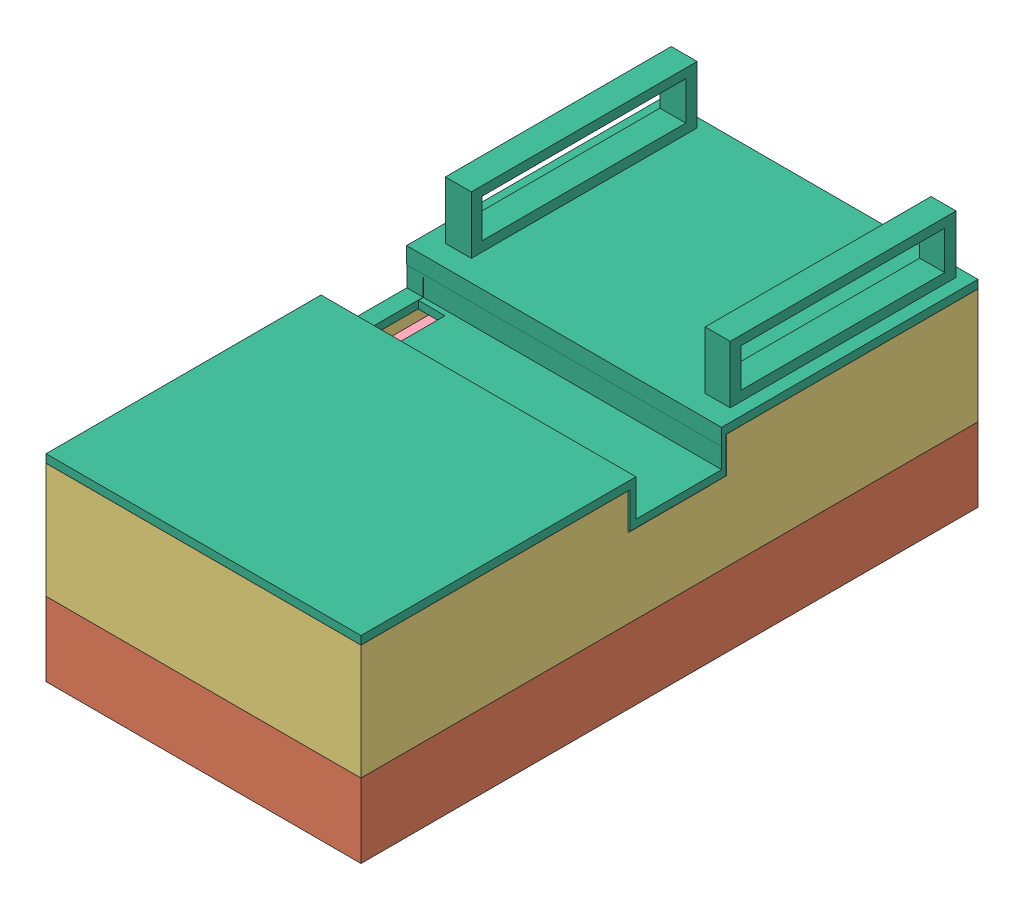
SolidWorks assembly Assembly, configuration Predeterminado. Lengths in mm.
Overall size (39.21 31 75).
73 component instances, 24 part files, 9 mates.
Components (placement in the parent):
- Batery-1: Batery [Predeterminado] at (30.2546 13.9223 39.5238) size (18 7 52)
- BatterySlot-1: BatterySlot [Predeterminado] at (30.3046 11.7897 39.4738) size (38.3 12 75)
- PCBSlot-1: PCBSlot [Predeterminado] at (30.3046 20.7768 39.4738) size (38.3 14 75)
- TFG_PSoC_PCB.step-1: TFG_PSoC_PCB.step [Predeterminado] at (15.3186 27.933 71.5458) x (1 0 0) z (0 1 0) size (30.68 63.5 8.39)
  - Board.step-1: Board.step [Predeterminado] at origin size (28.96 63.5 1.13)
    - Open CASCADE STEP translator 6.8 1.1.1.step-1: Open CASCADE STEP translator 6.8 1.1.1.step [Predeterminado] at (0 0 -1.1244) size (28.96 63.5 1.13)
  - R6.step-1: R6.step [Predeterminado] at origin size (1.6 0.8 0.45)
    - 0603_resistor.step-1: 0603_resistor.step [Predeterminado] at (19.3041 13.697 0) x (-1 0 0) z (0 1 0) size (1.6 0.45 0.8)
  - D3.step-1: D3.step [Predeterminado] at origin size (3.2 1.6 0.9)
    - LED_1206_Base_BLUE.step-1: LED_1206_Base_BLUE.step [Predeterminado] at (3.1748 36.322 0) x (-1 0 0) z (0 1 0) size (3.2 0.4 1.6)
    - LED_1206_Lens_BLUE.step-1: LED_1206_Lens_BLUE.step [Predeterminado] at (3.1749 36.3219 0) x (-1 0 0) z (0 1 0) size (1.5 0.6 1.6)
  - U4.step-1: U4.step [Predeterminado] at origin size (2.9 2.7 1.45)
    - OT.step-1: OT.step [Predeterminado] at (15.3671 10.9219 0) x (1 0 0) z (0 -1 0) size (2.9 1.45 2.7)
  - U3.step-1: U3.step [Predeterminado] at origin size (6.5 7 1.8)
    - ADP3338AKCZ-3.3-RL.step-1: ADP3338AKCZ-3.3-RL.step [Predeterminado] at (25.2731 8.0009 0) x (0 -1 0) z (-1 0 0) size (7 1.8 6.5)
  - U2.step-1: U2.step [Predeterminado] at origin size (13.5 18.5 1.8)
    - HM11.step-1: HM11.step [Predeterminado] at (18.034 20.9359 -1.1244) x (1 0 0) z (0 0 -1) size (13.5 18.5 1.8)
  - U1.step-1: U1.step [Predeterminado] at origin size (8.1 8.1 1)
    - 6140338960.step-1: 6140338960.step [Predeterminado] at (14.224 43.942 0) x (1 0 0) z (0 0 1) size (8.1 8.1 1)
  - S1.step-1: S1.step [Predeterminado] at origin size (7.39 10.49 3.05)
    - NKK_SS312SAH4.step-1: NKK_SS312SAH4.step [Predeterminado] at (2.2801 20.701 0) x (0 -1 0) z (-1 0 0) size (10.49 3.05 7.39)
      - SS312SAH4.step-1: SS312SAH4.step [Predeterminado] at (0 1.4478 0) size (10.49 3.05 7.39)
        - SS312SAH4body.step-1: SS312SAH4body.step [Predeterminado] at origin size (9.45 2.9 3.99)
        - SS312SAH4actu.step-1: SS312SAH4actu.step [Predeterminado] at (0 0.5588 1.9431) x (1 0 0) z (0 -1 0) size (3.51 2.31 1.19)
        - SS312SAH4trmnls.step-1: SS312SAH4trmnls.step [Predeterminado] at (0 0 -1.8669) size (4.62 1.72 1.8)
        - SS312SAH4brac.step-1: SS312SAH4brac.step [Predeterminado] at origin size (10.49 2.9 3.99)
  - R5.step-1: R5.step [Predeterminado] at origin size (0.8 1.6 0.45)
    - 0603_resistor.step-1: 0603_resistor.step [Predeterminado] at (18.65 35.8139 0) x (0 1 0) z (1 0 0) size (1.6 0.45 0.8)
  - R4.step-1: R4.step [Predeterminado] at origin size (1.6 0.8 0.45)
    - 0603_resistor.step-1: 0603_resistor.step [Predeterminado] at (23.4951 51.797 0) x (-1 0 0) z (0 1 0) size (1.6 0.45 0.8)
  - R3.step-1: R3.step [Predeterminado] at origin size (1.6 0.8 0.45)
    - 0603_resistor.step-1: 0603_resistor.step [Predeterminado] at (15.4941 6.839 0) x (-1 0 0) z (0 1 0) size (1.6 0.45 0.8)
  - R2.step-1: R2.step [Predeterminado] at origin size (0.8 1.6 0.45)
    - 0603_resistor.step-1: 0603_resistor.step [Predeterminado] at (12.211 7.2391 0) x (0 -1 0) z (-1 0 0) size (1.6 0.45 0.8)
  - R1.step-1: R1.step [Predeterminado] at origin size (0.8 1.6 0.45)
    - 0603_resistor.step-1: 0603_resistor.step [Predeterminado] at (12.211 10.2871 0) x (0 -1 0) z (-1 0 0) size (1.6 0.45 0.8)
  - J2.step-1: J2.step [Predeterminado] at origin size (7.9 8.94 3.96)
    - Molex_-_1054500101_v7.step-1: Molex_-_1054500101_v7.step [Predeterminado] at (4.6431 8.7717 0) x (0 1 0) z (0 0 1) size (8.94 7.9 3.96)
  - J1.step-1: J1.step [Predeterminado] at origin size (6.35 5.84 5.97)
    - 6140336880.step-1: 6140336880.step [Predeterminado] at (3.556 54.8868 0) x (-1 0 0) z (0 1 0) size (6.35 5.97 5.84)
  - D2.step-1: D2.step [Predeterminado] at origin size (3.2 1.6 0.9)
    - LED_1206_Base_GREEN.step-1: LED_1206_Base_GREEN.step [Predeterminado] at (3.1748 31.877 0) x (-1 0 0) z (0 1 0) size (3.2 0.4 1.6)
    - LED_1206_Lens_GREEN.step-1: LED_1206_Lens_GREEN.step [Predeterminado] at (3.1749 31.8769 0) x (-1 0 0) z (0 1 0) size (1.5 0.6 1.6)
  - D1.step-1: D1.step [Predeterminado] at origin size (3.2 1.6 0.9)
    - LED_1206_Lens_YELLOW.step-1: LED_1206_Lens_YELLOW.step [Predeterminado] at (3.1751 29.2728 0) x (1 0 0) z (0 -1 0) size (1.5 0.6 1.6)
    - LED_1206_Base_YELLOW.step-1: LED_1206_Base_YELLOW.step [Predeterminado] at (3.1752 29.2728 0) x (1 0 0) z (0 -1 0) size (3.2 0.4 1.6)
  - C13.step-1: C13.step [Predeterminado] at origin size (0.82 1.6 0.82)
    - 0603_cap.step-1: 0603_cap.step [Predeterminado] at (13.4621 57.2769 0) x (0 -1 0) z (-1 0 0) size (1.6 0.82 0.82)
  - C12.step-1: C12.step [Predeterminado] at origin size (0.82 1.6 0.82)
    - 0603_cap.step-1: 0603_cap.step [Predeterminado] at (15.2664 57.2769 0) x (0 -1 0) z (-1 0 0) size (1.6 0.82 0.82)
  - C11.step-1: C11.step [Predeterminado] at origin size (0.82 1.6 0.82)
    - 0603_cap.step-1: 0603_cap.step [Predeterminado] at (10.0329 35.6871 0) x (0 1 0) z (1 0 0) size (1.6 0.82 0.82)
  - C10.step-1: C10.step [Predeterminado] at origin size (0.82 1.6 0.82)
    - 0603_cap.step-1: 0603_cap.step [Predeterminado] at (8.2287 35.6871 0) x (0 1 0) z (1 0 0) size (1.6 0.82 0.82)
  - C9.step-1: C9.step [Predeterminado] at origin size (1.6 0.82 0.82)
    - 0603_cap.step-1: 0603_cap.step [Predeterminado] at (23.4949 49.7839 0) x (-1 0 0) z (0 1 0) size (1.6 0.82 0.82)
  - C8.step-1: C8.step [Predeterminado] at origin size (1.6 0.82 0.82)
    - 0603_cap.step-1: 0603_cap.step [Predeterminado] at (23.4949 47.8789 0) x (-1 0 0) z (0 1 0) size (1.6 0.82 0.82)
  - C7.step-1: C7.step [Predeterminado] at origin size (0.82 1.6 0.82)
    - 0603_cap.step-1: 0603_cap.step [Predeterminado] at (10.2871 57.2369 0) x (0 -1 0) z (-1 0 0) size (1.6 0.82 0.82)
  - C6.step-1: C6.step [Predeterminado] at origin size (0.82 1.6 0.82)
    - 0603_cap.step-1: 0603_cap.step [Predeterminado] at (4.5721 39.2429 0) x (0 -1 0) z (-1 0 0) size (1.6 0.82 0.82)
  - C5.step-1: C5.step [Predeterminado] at origin size (0.82 1.6 0.82)
    - 0603_cap.step-1: 0603_cap.step [Predeterminado] at (18.2881 54.9509 0) x (0 -1 0) z (-1 0 0) size (1.6 0.82 0.82)
  - C4.step-1: C4.step [Predeterminado] at origin size (1.6 0.82 0.82)
    - 0603_cap.step-1: 0603_cap.step [Predeterminado] at (26.5429 13.3349 0) x (-1 0 0) z (0 1 0) size (1.6 0.82 0.82)
  - C3.step-1: C3.step [Predeterminado] at origin size (0.82 1.6 0.82)
    - 0603_cap.step-1: 0603_cap.step [Predeterminado] at (18.6691 10.4539 0) x (0 -1 0) z (-1 0 0) size (1.6 0.82 0.82)
  - C2.step-1: C2.step [Predeterminado] at origin size (1.27 2 1.27)
    - 0805_cap.step-1: 0805_cap.step [Predeterminado] at (18.032 6.4771 0.62) x (0 -1 0) z (0 0 1) size (2 1.27 1.27)
  - C1.step-1: C1.step [Predeterminado] at origin size (1.27 2 1.27)
    - 0805_cap.step-1: 0805_cap.step [Predeterminado] at (10.416 8.6739 0.62) x (0 1 0) z (0 0 1) size (2 1.27 1.27)
- TAPA-3: TAPA [Predeterminado] at (30.2994 35.7867 39.4738) x (-1 0 0) z (0 0 1) size (38.29 12.38 75)
Mates (geometry in assembly coordinates):
- Coincidente1: coincident anti-aligned: plane of Batery-1 through (21.2546 20.9223 65.5238) normal (0 0 1); plane of BatterySlot-1 through (30.3046 13.5897 65.5238) normal (0 0 -1)
- Coincidente2: coincident anti-aligned: plane of Batery-1 through (21.2546 20.9223 13.5238) normal (-1 0 0); plane of BatterySlot-1 through (21.2546 13.5897 39.4738) normal (1 0 0)
- Paralelo7: parallel anti-aligned: plane of PCBSlot-1 through (30.3046 20.7768 39.4738) normal (0 -1 0); plane of TFG_PSoC_PCB.step-1/Board.step-1/Open CASCADE STEP translator 6.8 1.1.1.step-1 through (15.3186 27.933 71.5458) normal (0 1 0)
- Concéntrica23: concentric aligned: cylinder of PCBSlot-1 through (42.3696 31.7768 69.5138) axis (0 -1 0) radius 1.14; cylinder of TFG_PSoC_PCB.step-1/Board.step-1/Open CASCADE STEP translator 6.8 1.1.1.step-1 through (42.3696 26.8086 69.5138) axis (0 -1 0) radius 1.27
- Concéntrica27: concentric aligned: cylinder of PCBSlot-1 through (42.3696 31.7768 9.8238) axis (0 -1 0) radius 1.14; cylinder of TFG_PSoC_PCB.step-1/Board.step-1/Open CASCADE STEP translator 6.8 1.1.1.step-1 through (42.3696 26.8086 9.8238) axis (0 -1 0) radius 1.27
- Concéntrica28: concentric aligned: cylinder of PCBSlot-1 through (33.6567 31.7768 74.3238) axis (0 1 0) radius 1.75; cylinder of TAPA-3 through (33.6567 31.7867 74.3238) axis (0 1 0) radius 1.745
- Concéntrica29: concentric aligned: cylinder of PCBSlot-1 through (33.6567 31.7768 4.6238) axis (0 1 0) radius 1.75; cylinder of TAPA-3 through (33.6567 31.7867 4.6238) axis (0 1 0) radius 1.75
- Concéntrica30: concentric aligned: cylinder of BatterySlot-1 through (33.6567 23.7897 4.6238) axis (0 -1 0) radius 1.75; cylinder of PCBSlot-1 through (33.6567 23.7768 4.6238) axis (0 -1 0) radius 1.75
- Concéntrica31: concentric aligned: cylinder of BatterySlot-1 through (33.6567 23.7897 74.3238) axis (0 -1 0) radius 1.745; cylinder of PCBSlot-1 through (33.6567 23.7768 74.3238) axis (0 -1 0) radius 1.75
